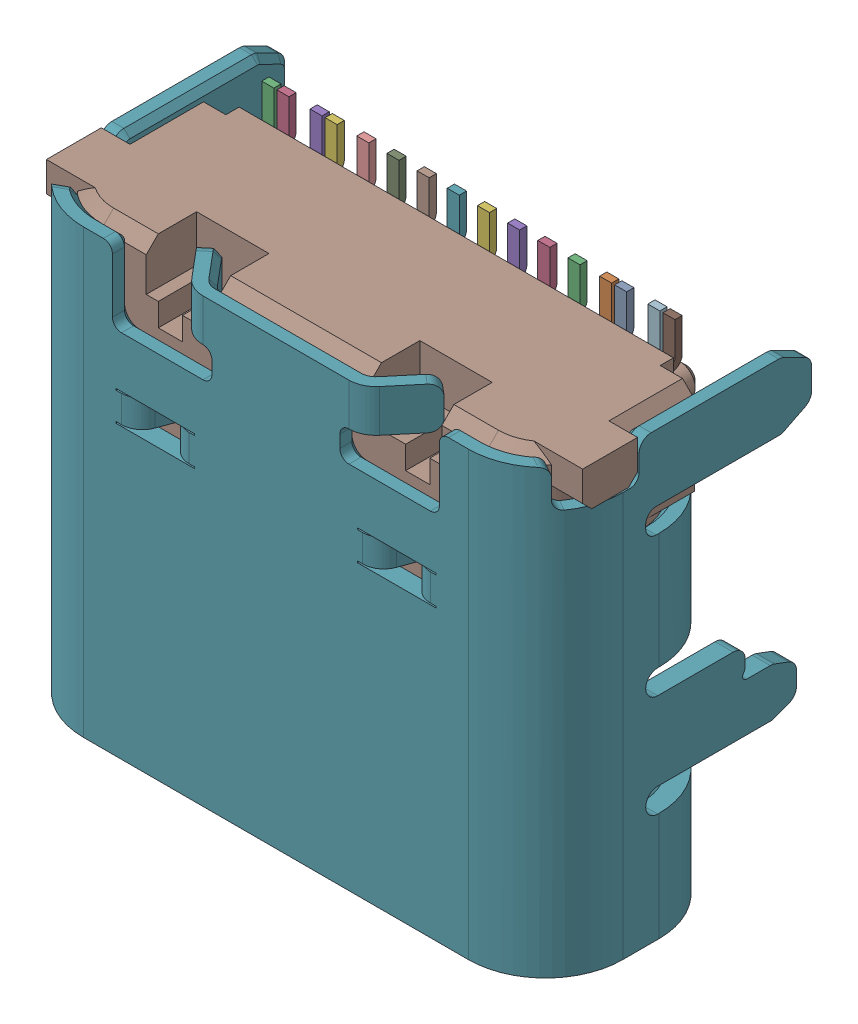
SolidWorks assembly J5, configuration Predeterminado. Lengths in mm.
Overall size (8.94 7.71 4.41).
47 component instances, 44 part files, 0 mates.
Components (placement in the parent):
- Open CASCADE STEP translator 6.8 1.16.1-1: Open CASCADE STEP translator 6.8 1.16.1 [Predeterminado] at origin size (8.94 7.71 4.41)
  - Body_1_5-1: Body_1_5 [Predeterminado] at (3.2 -4.8 0) x (1 0 0) z (0 -1 0) size (8.94 4.41 7.71)
    - Imported_2-1: Imported_2 [Predeterminado] at (0 0 -1.255) size (8.94 4.41 7.71)
      - SOLID_41-1: SOLID_41 [Predeterminado] at origin size (0.25 0.05 2.38)
      - SOLID_42-1: SOLID_42 [Predeterminado] at origin size (0.25 0.05 2.38)
      - SOLID_43-1: SOLID_43 [Predeterminado] at origin size (0.25 0.05 1.88)
      - SOLID_44-1: SOLID_44 [Predeterminado] at origin size (0.25 0.05 1.88)
      - SOLID_45-1: SOLID_45 [Predeterminado] at origin size (0.25 0.05 1.88)
      - SOLID_46-1: SOLID_46 [Predeterminado] at origin size (0.25 0.05 1.88)
      - SOLID_47-1: SOLID_47 [Predeterminado] at origin size (0.25 0.05 1.88)
      - SOLID_48-1: SOLID_48 [Predeterminado] at origin size (0.25 0.05 1.88)
      - SOLID_49-1: SOLID_49 [Predeterminado] at origin size (0.25 0.05 1.88)
      - SOLID_50-1: SOLID_50 [Predeterminado] at origin size (0.25 0.05 1.88)
      - SOLID_51-1: SOLID_51 [Predeterminado] at origin size (0.25 0.05 2.38)
      - SOLID_52-1: SOLID_52 [Predeterminado] at origin size (0.25 0.05 2.38)
      - SOLID_53-1: SOLID_53 [Predeterminado] at origin size (0.25 0.05 2.38)
      - SOLID_54-1: SOLID_54 [Predeterminado] at origin size (0.25 0.05 1.88)
      - SOLID_55-1: SOLID_55 [Predeterminado] at origin size (0.25 0.05 1.88)
      - SOLID_56-1: SOLID_56 [Predeterminado] at origin size (0.25 0.05 2.38)
      - SOLID_57-1: SOLID_57 [Predeterminado] at origin size (0.25 0.05 1.88)
      - SOLID_58-1: SOLID_58 [Predeterminado] at origin size (0.25 0.05 1.88)
      - SOLID_59-1: SOLID_59 [Predeterminado] at origin size (0.25 0.05 1.88)
      - SOLID_60-1: SOLID_60 [Predeterminado] at origin size (0.25 0.05 1.88)
      - SOLID_61-1: SOLID_61 [Predeterminado] at origin size (0.25 0.05 2.38)
      - SOLID_62-1: SOLID_62 [Predeterminado] at origin size (0.25 0.05 1.88)
      - SOLID_63-1: SOLID_63 [Predeterminado] at origin size (0.25 0.05 1.88)
      - SOLID_64-1: SOLID_64 [Predeterminado] at origin size (0.25 0.05 2.38)
      - SOLID_65-1: SOLID_65 [Predeterminado] at origin size (0.35 0.1 1.82)
      - SOLID_66-1: SOLID_66 [Predeterminado] at origin size (0.35 0.1 1.82)
      - SOLID_67-1: SOLID_67 [Predeterminado] at origin size (0.2 0.32 0.73)
      - SOLID_68-1: SOLID_68 [Predeterminado] at origin size (0.2 0.32 0.73)
      - SOLID_69-1: SOLID_69 [Predeterminado] at origin size (0.2 0.32 0.73)
      - SOLID_70-1: SOLID_70 [Predeterminado] at origin size (0.2 0.32 0.73)
      - SOLID_71-1: SOLID_71 [Predeterminado] at origin size (0.2 0.32 0.73)
      - SOLID_72-1: SOLID_72 [Predeterminado] at origin size (0.2 0.32 0.73)
      - SOLID_73-1: SOLID_73 [Predeterminado] at origin size (0.2 0.32 0.73)
      - SOLID_74-1: SOLID_74 [Predeterminado] at origin size (0.2 0.32 0.73)
      - SOLID_75-1: SOLID_75 [Predeterminado] at origin size (0.2 0.32 0.73)
      - SOLID_76-1: SOLID_76 [Predeterminado] at origin size (0.2 0.32 0.73)
      - SOLID_77-1: SOLID_77 [Predeterminado] at origin size (0.2 0.32 0.73)
      - SOLID_78-1: SOLID_78 [Predeterminado] at origin size (0.2 0.32 0.73)
      - SOLID_79-1: SOLID_79 [Predeterminado] at origin size (0.2 0.32 0.73)
      - SOLID_80-1: SOLID_80 [Predeterminado] at origin size (0.2 0.32 0.73)
      - SOLID_81-1: SOLID_81 [Predeterminado] at origin size (0.2 0.32 0.73)
      - SOLID_82-1: SOLID_82 [Predeterminado] at origin size (0.2 0.32 0.73)
      - SOLID_83-1: SOLID_83 [Predeterminado] at origin size (8.94 4.41 7.34)
      - SOLID_84-1: SOLID_84 [Predeterminado] at origin size (8.89 3.61 6.57)
